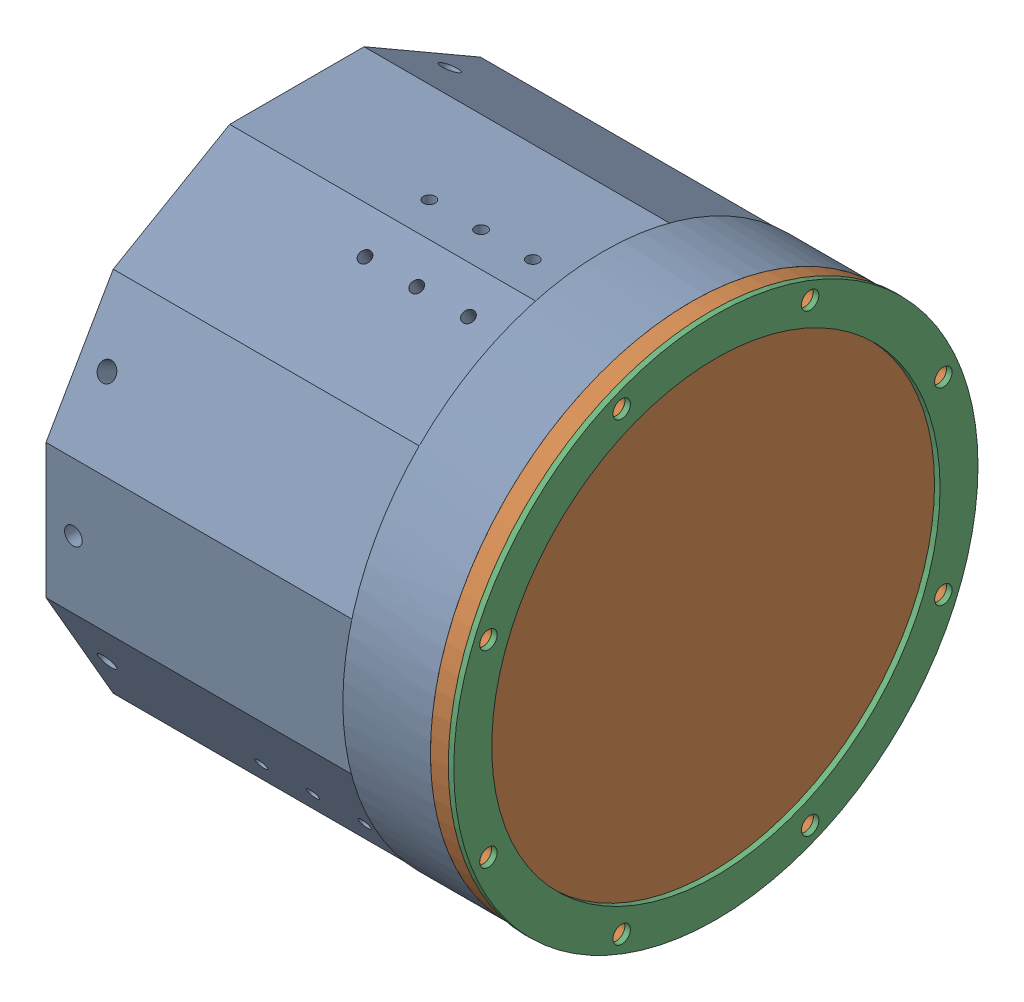
SolidWorks assembly Pump_Hull_Assembly, configuration Default. Lengths in mm.
Overall size (121.5 197.46 197.46).
3 component instances, 3 part files, 6 mates.
Components (placement in the parent):
- Pump_Hull-1: Pump_Hull [Default] at (511.806 883.7847 1306.411) size (114.3 151.13 151.13)
- Main_Hull_Lens-1: Main_Hull_Lens [Default] at (626.106 883.7847 1306.411) x (0 -0.92388 -0.382683) z (1 0 0) size (151.13 151.13 5.6)
- Main_Hull_Lens_Ring-1: Main_Hull_Lens_Ring [Default] at (631.706 883.7847 1306.411) x (0 0 -1) z (1 0 0) size (152 152 1.6)
Mates (geometry in assembly coordinates):
- Coincident1: coincident aligned: plane of Pump_Hull-1 through (626.106 883.7847 1369.4968) normal (1 0 0); circle of Main_Hull_Lens-1
- Concentric1: concentric aligned: circle of Pump_Hull-1; circle of Main_Hull_Lens-1
- Coincident2: coincident aligned: circle of Pump_Hull-1; circle of Main_Hull_Lens-1
- Coincident3: coincident anti-aligned: circle of Main_Hull_Lens-1; plane of Main_Hull_Lens_Ring-1 through (631.706 883.7847 1306.411) normal (-1 0 0)
- Concentric2: concentric anti-aligned: cylinder of Pump_Hull-1 through (527.681 883.7847 1306.411) axis (1 0 0) radius 75.565; cylinder of Main_Hull_Lens_Ring-1 through (633.306 883.7847 1306.411) axis (-1 0 0) radius 76
- Concentric3: concentric aligned: cylinder of Pump_Hull-1 through (626.106 817.832 1333.7295) axis (1 0 0) radius 1.7272; cylinder of Main_Hull_Lens_Ring-1 through (633.306 817.832 1333.7295) axis (1 0 0) radius 2.5273
